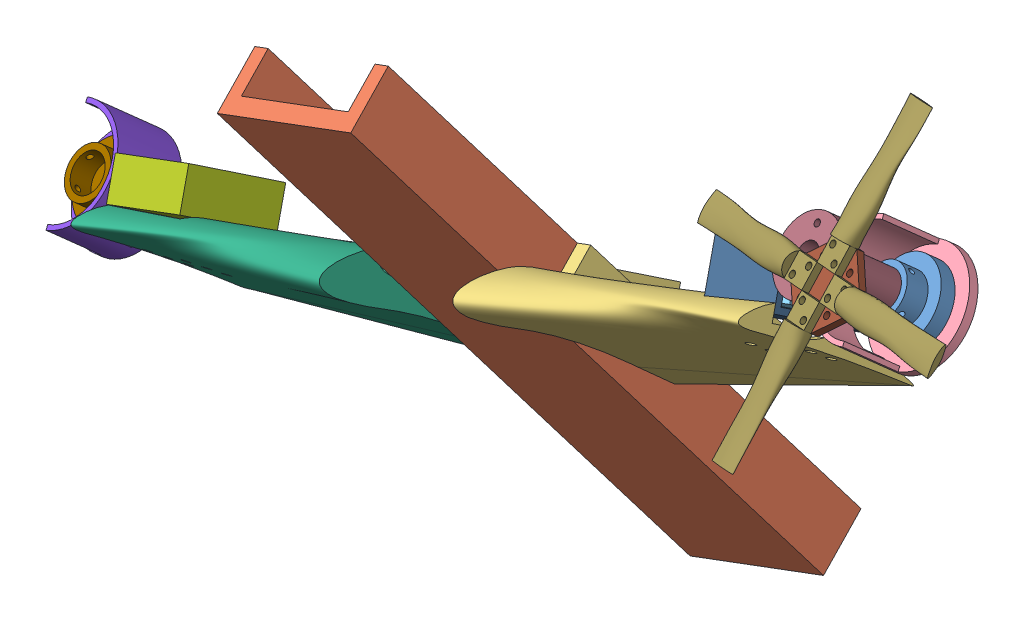
SolidWorks assembly group, configuration Standard. Lengths in mm.
Overall size (360 291.4 207.16).
16 component instances, 13 part files, 27 mates.
Components (placement in the parent):
- rotor-1: rotor [Standard] at (-3.8885 13.6124 59.6831) x (0.393717 0.75732 -0.521012) z (-0.235383 0.630953 0.739252) size (30 30 40)
- bulk-1: bulk [Standard] at (-128.0172 -138.5367 1.0347) x (0.936926 0.349529 0) z (-0.295464 0.792001 0.534261) size (50 20 200)
- wing-1: wing [Standard] at (-119.496 -31.6545 68.9981) x (0.936926 0.349529 0) z (-0.187819 0.503456 0.84336) size (110 36.92 78.5)
- rotorhull-1: rotorhull [Standard] at (-3.8885 13.6124 59.6831) x (0.936926 0.349529 0) z (-0.235383 0.630953 0.739252) size (35 35 23)
- servomotor-1: servomotor [Standard] at (-26.7661 14.4617 58.0398) x (-0.294779 0.790166 -0.537349) z (-0.187819 0.503456 0.84336) size (13 37.5 33)
- Spiegelnwing-4: Spiegelnwing [Standard] at (-166.3423 -49.131 68.9981) x (-0.936926 -0.349529 0) z (0.187819 -0.503456 -0.84336) size (110 29.67 78.5)
- Spiegelnservomotor-5: Spiegelnservomotor [Standard] at (-266.619 -75.0178 58.0398) x (-0.294779 0.790166 -0.537349) z (0.187819 -0.503456 -0.84336) size (13 37.5 33)
- Spiegelnrotorhull-5: Spiegelnrotorhull [Standard] at (-283.3504 -90.6435 59.6831) x (-0.936926 -0.349529 0) z (0.235383 -0.630953 -0.739252) size (35 35 23)
- Spiegelnrotor-5: Spiegelnrotor [Standard] at (-283.3504 -90.6435 59.6831) x (-0.793534 0.314405 -0.521012) z (0.235383 -0.630953 -0.739252) size (25 25 12.5)
- servo_motor_hul-1: servo_motor_hul [Standard] at (-37.7653 -2.5456 69.9627) x (0.187819 -0.503456 -0.84336) z (0.936926 0.349529 0) size (37 18 26.5)
- rotor_plate-1: rotor_plate [Standard] at (0.2709 38.0723 94.2397) x (-0.03026 -0.765012 0.643304) z (-0.235383 0.630953 0.739252) size (24 24 2.5)
- rotor_wing_single-1: rotor_wing_single [Standard] at (-0.2487 49.6185 89.2923) x (0.03026 0.765012 -0.643304) z (0.971432 0.129053 0.199163) size (82.56 116.28 10.25)
- rotor_wing_single-2: rotor_wing_single [Standard] at (-12.2689 38.8897 94.622) x (-0.971432 -0.129053 -0.199163) z (0.03026 0.765012 -0.643304) size (82.56 116.28 10.25)
- rotor_wing_single-3: rotor_wing_single [Standard] at (-0.9749 31.2583 104.7315) x (-0.03026 -0.765012 0.643304) z (-0.971432 -0.129053 -0.199163) size (82.56 116.28 10.25)
- rotor_wing_single-4: rotor_wing_single [Standard] at (11.0454 41.9871 99.4018) x (0.971432 0.129053 0.199163) z (-0.03026 -0.765012 0.643304) size (82.56 116.28 10.25)
- rotor_part2-1: rotor_part2 [Standard] at (-3.8885 13.6124 59.6831) x (-0.393717 -0.75732 0.521012) z (-0.235383 0.630953 0.739252) size (30 30 40)
Mates (geometry in assembly coordinates):
- Deckungsgleich4: coincident aligned: circle of bulk-1; circle of wing-1
- Konzentrisch7: concentric anti-aligned: circle of bulk-1; circle of wing-1
- Deckungsgleich14: coincident: circle of rotor-1; circle of rotorhull-1
- Deckungsgleich18: coincident anti-aligned: plane of servomotor-1 through (-52.5315 4.8496 58.0398) normal (-0.936926 -0.349529 0); plane of servo_motor_hul-1 through (-48.3058 -6.4778 69.9627) normal (0.936926 0.349529 0)
- Deckungsgleich19: coincident anti-aligned: plane of servomotor-1 through (-49.9232 -2.1421 47.4497) normal (-0.294779 0.790166 -0.537349); plane of servo_motor_hul-1 through (-23.6893 7.6447 47.4497) normal (0.294779 -0.790166 0.537349)
- Deckungsgleich20: coincident anti-aligned: plane of servomotor-1 through (-56.1212 14.4719 75.2806) normal (-0.187819 0.503456 0.84336); plane of servo_motor_hul-1 through (-25.7604 13.1964 82.8035) normal (0.187819 -0.503456 -0.84336)
- Konzentrisch9: concentric anti-aligned: cylinder of rotorhull-1 through (-43.0132 4.048 64.8579) axis (0.936926 0.349529 0) radius 5; circle of servomotor-1
- Konzentrisch10: concentric aligned: cylinder of rotor-1 through (-13.3038 38.8506 89.2532) axis (-0.235383 0.630953 0.739252) radius 6; cylinder of rotor_part2-1 through (-13.3038 38.8506 89.2532) axis (-0.235383 0.630953 0.739252) radius 6
- Konzentrisch11: concentric anti-aligned: cylinder of rotor-1 through (-11.1638 10.4555 73.5883) axis (0.393717 0.75732 -0.521012) radius 1; cylinder of rotor_part2-1 through (-1.5178 29.0098 60.8235) axis (-0.393717 -0.75732 0.521012) radius 1
- Deckungsgleich45: coincident anti-aligned: plane of rotor-1 through (-3.8885 13.6124 59.6831) normal (0.235383 -0.630953 -0.739252); plane of rotorhull-1 through (-3.8885 13.6124 59.6831) normal (-0.235383 0.630953 0.739252)
- Konzentrisch17: concentric aligned: circle of rotor-1; circle of rotorhull-1
- Konzentrisch18: concentric aligned: circle of rotor_plate-1; circle of rotor_wing_single-1
- Konzentrisch19: concentric aligned: circle of rotor_plate-1; circle of rotor_wing_single-1
- Deckungsgleich50: coincident anti-aligned: plane of rotor_plate-1 through (-0.3176 39.6497 96.0879) normal (-0.235383 0.630953 0.739252); plane of rotor_wing_single-1 through (0.0455 48.8298 88.3682) normal (0.235383 -0.630953 -0.739252)
- Konzentrisch23: concentric aligned: circle of rotor_plate-1; circle of rotor_wing_single-4
- Konzentrisch24: concentric aligned: circle of rotor_plate-1; circle of rotor_wing_single-4
- Deckungsgleich57: coincident anti-aligned: plane of rotor_plate-1 through (-0.3176 39.6497 96.0879) normal (-0.235383 0.630953 0.739252); plane of rotor_wing_single-4 through (11.3396 41.1984 98.4778) normal (0.235383 -0.630953 -0.739252)
- Konzentrisch25: concentric aligned: circle of rotor_plate-1; circle of rotor_wing_single-2
- Konzentrisch26: concentric aligned: circle of rotor_plate-1; circle of rotor_wing_single-2
- Deckungsgleich61: coincident anti-aligned: plane of rotor_plate-1 through (-0.3176 39.6497 96.0879) normal (-0.235383 0.630953 0.739252); plane of rotor_wing_single-2 through (-11.9747 38.101 93.6979) normal (0.235383 -0.630953 -0.739252)
- Konzentrisch28: concentric aligned: circle of rotor_plate-1; circle of rotor_wing_single-3
- Konzentrisch30: concentric aligned: circle of rotor_plate-1; circle of rotor_wing_single-3
- Deckungsgleich66: coincident anti-aligned: plane of rotor_plate-1 through (-0.3176 39.6497 96.0879) normal (-0.235383 0.630953 0.739252); plane of rotor_wing_single-3 through (-0.6807 30.4697 103.8074) normal (0.235383 -0.630953 -0.739252)
- Konzentrisch31: concentric aligned: circle of rotor_plate-1; circle of rotor_part2-1
- Deckungsgleich71: coincident anti-aligned: plane of rotor_plate-1 through (0.2709 38.0723 94.2397) normal (0.235383 -0.630953 -0.739252); plane of rotor_part2-1 through (-13.3038 38.8506 89.2532) normal (-0.235383 0.630953 0.739252)
- Konzentrisch32: concentric anti-aligned: cylinder of wing-1 through (-25.419 -10.6068 85.8247) axis (-0.294779 0.790166 -0.537349) radius 1.5; cylinder of servo_motor_hul-1 through (-32.0611 7.1977 73.7168) axis (0.294779 -0.790166 0.537349) radius 1.5
- Konzentrisch33: concentric anti-aligned: cylinder of wing-1 through (-22.7895 -17.6551 74.0176) axis (-0.294779 0.790166 -0.537349) radius 1.5; cylinder of servo_motor_hul-1 through (-29.4316 0.1493 61.9098) axis (0.294779 -0.790166 0.537349) radius 1.5
